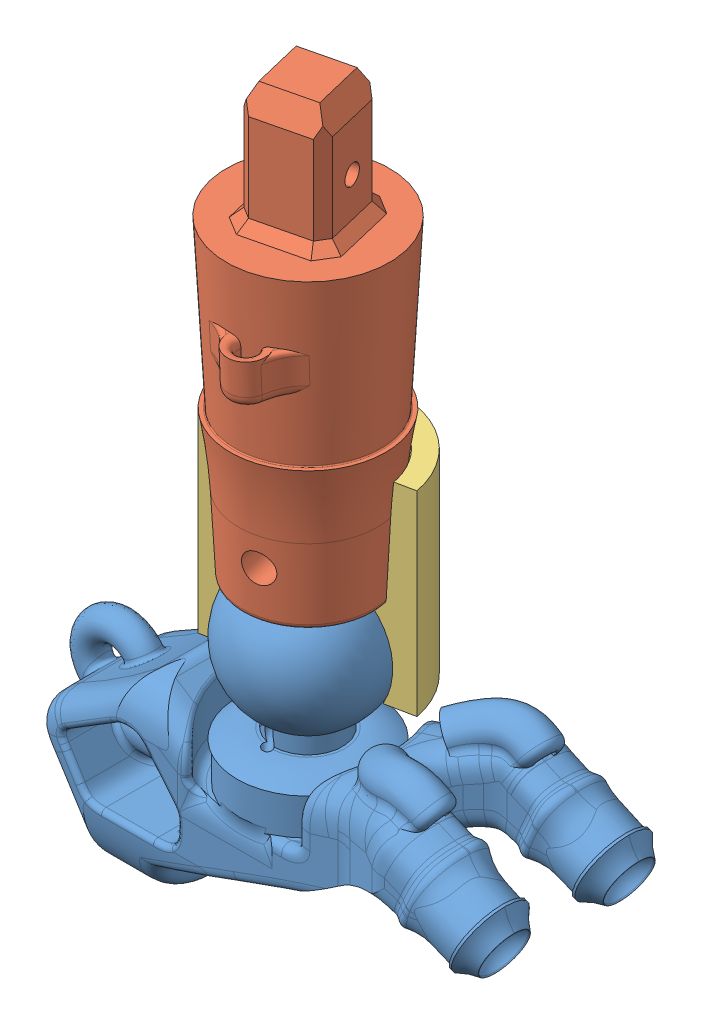
SolidWorks assembly Sleeve-redone, configuration Default. Lengths in mm.
Overall size (131.32 194.13 59.71).
3 component instances, 3 part files, 3 mates.
Components (placement in the parent):
- Talus - New-1: Talus - New [Default] at (-41.9179 75.1883 158.1192) size (131.32 86.19 51)
- Tibial End-1: Tibial End [Default] at (-41.9179 68.1912 158.1192) x (0.972289 0 -0.233781) z (0.233781 0 0.972289) size (42.45 113.08 48.21)
- Part1-1: Part1 [Default] at (16.9126 66.487 51.6328) x (0.979688 0 -0.200529) z (0.200529 0 0.979688) size (48.26 50.8 24.7)
Mates (geometry in assembly coordinates):
- Tangent1: tangent: sphere of Talus - New-1; circle of Tibial End-1
- Concentric1: concentric: circle of Talus - New-1; circle of Tibial End-1
- Concentric2: concentric: circle of Tibial End-1; circle of Part1-1
